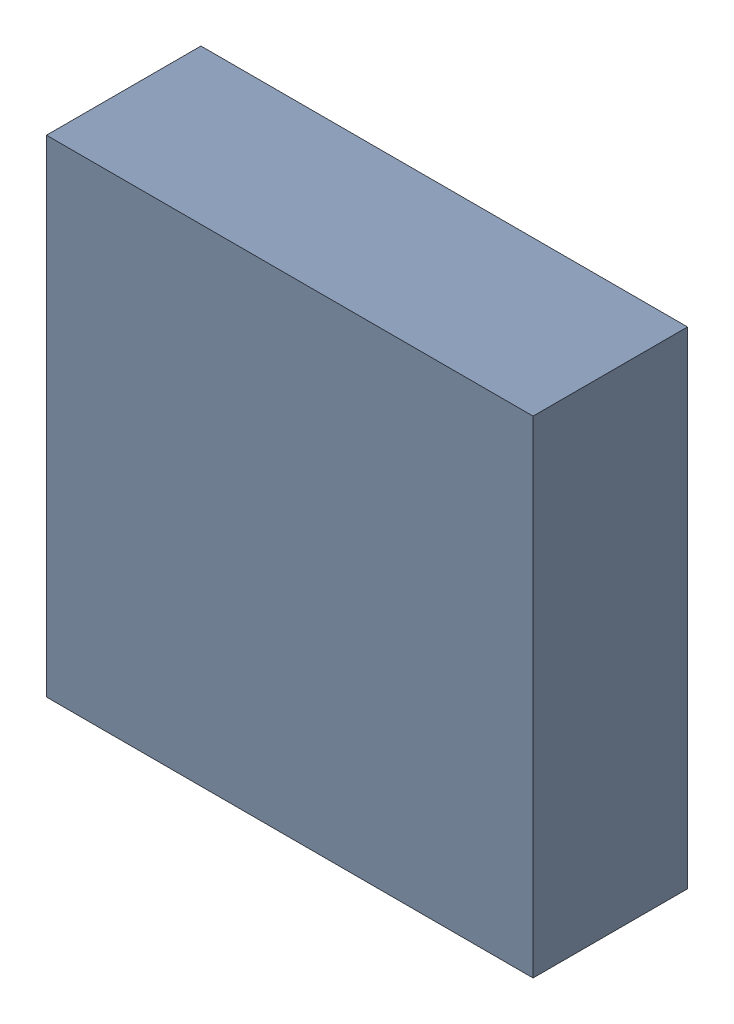
SolidWorks assembly U403PCB, configuration Default. Lengths in mm.
Overall size (3.15 3.15 1).
2 component instances, 1 part files, 0 mates.
Components (placement in the parent):
- 846484104-1: 846484104 [Default] at (119.8 103.2 -2.6638) size (3.15 3.15 1)
  - Extruded_20-1: Extruded_20 [Default] at origin size (3.15 3.15 1)
